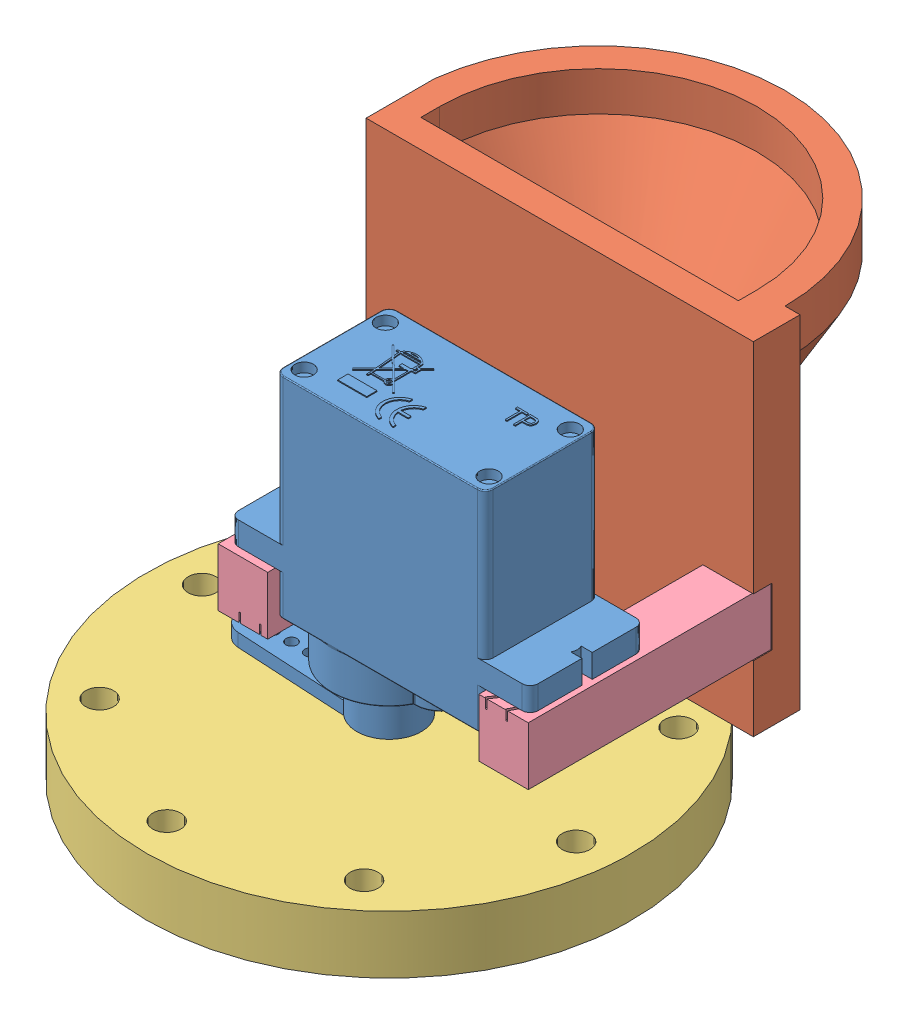
SolidWorks assembly Powder Dispense Assemnly 8T, configuration Default. Lengths in mm.
Overall size (56.28 43.04 70.24).
5 component instances, 4 part files, 11 mates.
Components (placement in the parent):
- servo9g better version-1: servo9g better version [Default] at (-107.7176 65.6461 170.209) x (1 0 0) z (0 0 -1) size (37.25 31.75 12.21)
- Powder Canister-2: Powder Canister [Default] at (-105.8943 59.5684 120.3258) size (41.46 36.64 25)
- AC_Base Plate_N1-2: AC_Base Plate_N1 [Default] at (-106.1943 21.5284 142.4258) x (0.086037 0 -0.996292) z (0.996292 0 0.086037) size (52 6.2 52)
- AC_powder bracket_N2-3: AC_powder bracket_N2 [Default] at (-117.5943 41.1784 149.3258) x (1 0 0) z (0 1 0) size (5.3 26 6.2)
- AC_powder bracket_N2-4: AC_powder bracket_N2 [Default] at (-84.3943 34.9784 149.3258) x (-1 0 0) z (0 -1 0) size (5.3 26 6.2)
Mates (geometry in assembly coordinates):
- Coincident20: coincident: plane of servo9g better version-1 through (-106.1943 27.7284 142.4258) normal (0 -1 0); plane of AC_Base Plate_N1-2 through (-106.1943 27.7284 142.4258) normal (0 1 0)
- Concentric3: concentric: cylinder of servo9g better version-1 through (-106.1943 29.1284 142.4258) axis (0 -1 0) radius 3.45; cylinder of AC_Base Plate_N1-2 through (-106.1943 27.7284 142.4258) axis (0 -1 0) radius 26
- Coincident21: coincident: plane of Powder Canister-2 through (-105.8943 59.5684 123.3258) normal (0 0 1); plane of AC_powder bracket_N2-3 through (-117.5943 41.1784 123.3258) normal (0 0 -1)
- Coincident22: coincident: plane of Powder Canister-2 through (-105.8943 41.1784 120.3258) normal (0 -1 0); plane of AC_powder bracket_N2-3 through (-117.5943 41.1784 123.3258) normal (0 1 0)
- Coincident23: coincident: plane of Powder Canister-2 through (-117.5943 59.5684 123.3258) normal (1 0 0); plane of AC_powder bracket_N2-3 through (-117.5943 41.1784 123.3258) normal (-1 0 0)
- Coincident24: coincident: plane of servo9g better version-1 through (-116.2443 41.1784 137.1758) normal (0 -1 0); plane of AC_powder bracket_N2-3 through (-117.5943 41.1784 123.3258) normal (0 1 0)
- Coincident25: coincident: plane of servo9g better version-1 through (-112.2943 -11.2163 147.6758) normal (-1 0 0); plane of AC_powder bracket_N2-3 through (-112.2943 41.1784 123.3258) normal (1 0 0)
- LimitDistance1: limit distance = 11 mm: plane of Powder Canister-2 through (-125.8943 19.5684 125.3258) normal (0 0 1); plane of servo9g better version-1 through (-111.4443 43.6784 136.3258) normal (0 0 -1)
- Coincident27: coincident: plane of Powder Canister-2 through (-89.6943 59.5684 123.3258) normal (1 0 0); plane of AC_powder bracket_N2-4 through (-89.6943 34.9784 123.3258) normal (-1 0 0)
- Coincident28: coincident: plane of Powder Canister-2 through (-105.8943 59.5684 123.3258) normal (0 0 1); plane of AC_powder bracket_N2-4 through (-84.3943 34.9784 123.3258) normal (0 0 -1)
- Coincident29: coincident: line of Powder Canister-2 through (-89.6943 34.9784 123.3258) axis (1 0 0); plane of AC_powder bracket_N2-4 through (-84.3943 34.9784 123.3258) normal (0 -1 0)
